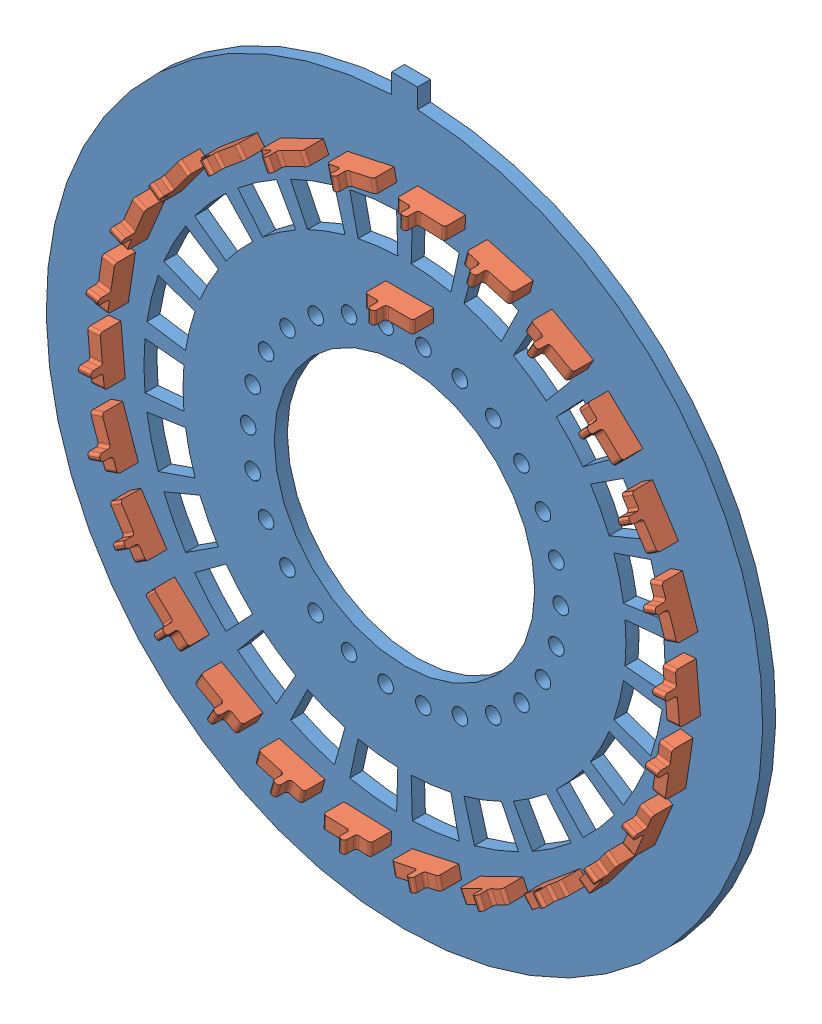
SolidWorks assembly indication pcb assembly, configuration Default. Lengths in mm.
Overall size (55 56.48 3.5).
28 component instances, 2 part files, 3 mates.
Components (placement in the parent):
- indication PCB-1: indication PCB [Default] at (21.3555 31.4598 41.8626) size (55 56.48 1)
- spring pin-1: spring pin [Default] at (43.9085 31.3248 43.6626) x (0.090499 -0.995897 0) z (-0.995897 -0.090499 0) size (3.66 2.5 0.96)
- spring pin-27: spring pin [Default] at (43.2208 25.9314 43.6626) x (-0.150465 -0.988615 0) z (-0.988615 0.150465 0) size (3.66 2.5 0.96)
- spring pin-28: spring pin [Default] at (41.2624 20.8593 43.6626) x (-0.382683 -0.92388 0) z (-0.92388 0.382683 0) size (3.66 2.5 0.96)
- spring pin-29: spring pin [Default] at (38.1471 16.4033 43.6626) x (-0.592662 -0.805451 0) z (-0.805451 0.592662 0) size (3.66 2.5 0.96)
- spring pin-30: spring pin [Default] at (34.0559 12.8224 43.6626) x (-0.768198 -0.640213 0) z (-0.640213 0.768198 0) size (3.66 2.5 0.96)
- spring pin-31: spring pin [Default] at (29.2266 10.3245 43.6626) x (-0.899088 -0.437768 0) z (-0.437768 0.899088 0) size (3.66 2.5 0.96)
- spring pin-32: spring pin [Default] at (23.9398 9.055 43.6626) x (-0.977727 -0.209881 0) z (-0.209881 0.977727 0) size (3.66 2.5 0.96)
- spring pin-33: spring pin [Default] at (18.5029 9.0876 43.6626) x (-0.999544 0.030203 0) z (0.030203 0.999544 0) size (3.66 2.5 0.96)
- spring pin-34: spring pin [Default] at (13.2318 10.4204 43.6626) x (-0.963271 0.268532 0) z (0.268532 0.963271 0) size (3.66 2.5 0.96)
- spring pin-35: spring pin [Default] at (8.4328 12.9759 43.6626) x (-0.871016 0.491255 0) z (0.491255 0.871016 0) size (3.66 2.5 0.96)
- spring pin-36: spring pin [Default] at (4.3848 16.6056 43.6626) x (-0.728141 0.685427 0) z (0.685427 0.728141 0) size (3.66 2.5 0.96)
- spring pin-37: spring pin [Default] at (1.323 21.0986 43.6626) x (-0.542949 0.839766 0) z (0.839766 0.542949 0) size (3.66 2.5 0.96)
- spring pin-38: spring pin [Default] at (-0.5745 26.1937 43.6626) x (-0.326203 0.9453 0) z (0.9453 0.326203 0) size (3.66 2.5 0.96)
- spring pin-39: spring pin [Default] at (-1.1975 31.5949 43.6626) x (-0.090499 0.995897 0) z (0.995897 0.090499 0) size (3.66 2.5 0.96)
- spring pin-40: spring pin [Default] at (-0.5098 36.9883 43.6626) x (0.150465 0.988615 0) z (0.988615 -0.150465 0) size (3.66 2.5 0.96)
- spring pin-41: spring pin [Default] at (1.4486 42.0604 43.6626) x (0.382683 0.92388 0) z (0.92388 -0.382683 0) size (3.66 2.5 0.96)
- spring pin-42: spring pin [Default] at (4.5639 46.5163 43.6626) x (0.592662 0.805451 0) z (0.805451 -0.592662 0) size (3.66 2.5 0.96)
- spring pin-43: spring pin [Default] at (8.6551 50.0973 43.6626) x (0.768198 0.640213 0) z (0.640213 -0.768198 0) size (3.66 2.5 0.96)
- spring pin-44: spring pin [Default] at (13.4844 52.5951 43.6626) x (0.899088 0.437768 0) z (0.437768 -0.899088 0) size (3.66 2.5 0.96)
- spring pin-45: spring pin [Default] at (18.7711 53.8647 43.6626) x (0.977727 0.209881 0) z (0.209881 -0.977727 0) size (3.66 2.5 0.96)
- spring pin-46: spring pin [Default] at (24.208 53.8321 43.6626) x (0.999544 -0.030203 0) z (-0.030203 -0.999544 0) size (3.66 2.5 0.96)
- spring pin-47: spring pin [Default] at (29.4792 52.4993 43.6626) x (0.963271 -0.268532 0) z (-0.268532 -0.963271 0) size (3.66 2.5 0.96)
- spring pin-48: spring pin [Default] at (34.2782 49.9438 43.6626) x (0.871016 -0.491255 0) z (-0.491255 -0.871016 0) size (3.66 2.5 0.96)
- spring pin-49: spring pin [Default] at (38.3262 46.3141 43.6626) x (0.728141 -0.685427 0) z (-0.685427 -0.728141 0) size (3.66 2.5 0.96)
- spring pin-50: spring pin [Default] at (41.3879 41.8211 43.6626) x (0.542949 -0.839766 0) z (-0.839766 -0.542949 0) size (3.66 2.5 0.96)
- spring pin-51: spring pin [Default] at (43.2854 36.726 43.6626) x (0.326203 -0.9453 0) z (-0.9453 -0.326203 0) size (3.66 2.5 0.96)
- spring pin-52: spring pin [Default] at (21.7527 46.348 43.6626) x (1 0 0) z (0 -1 0) size (3.66 2.5 0.96)
Mates (geometry in assembly coordinates):
- Coincident1: coincident anti-aligned: plane of indication PCB-1 through (21.3555 31.4598 42.8626) normal (0 0 1); plane of spring pin-1 through (42.7868 33.0604 42.8626) normal (0 0 -1)
- Parallel2: parallel anti-aligned: line of indication PCB-1 through (41.2734 33.2698 42.8626) axis (-0.995897 -0.090499 0); line of spring pin-1 through (42.7868 33.0604 44.2626) axis (0.995897 0.090499 0)
- Coincident5: coincident anti-aligned: plane of indication PCB-1 through (21.3555 31.4598 42.8626) normal (0 0 1); plane of spring pin-52 through (19.9227 45.388 42.8626) normal (0 0 -1)
